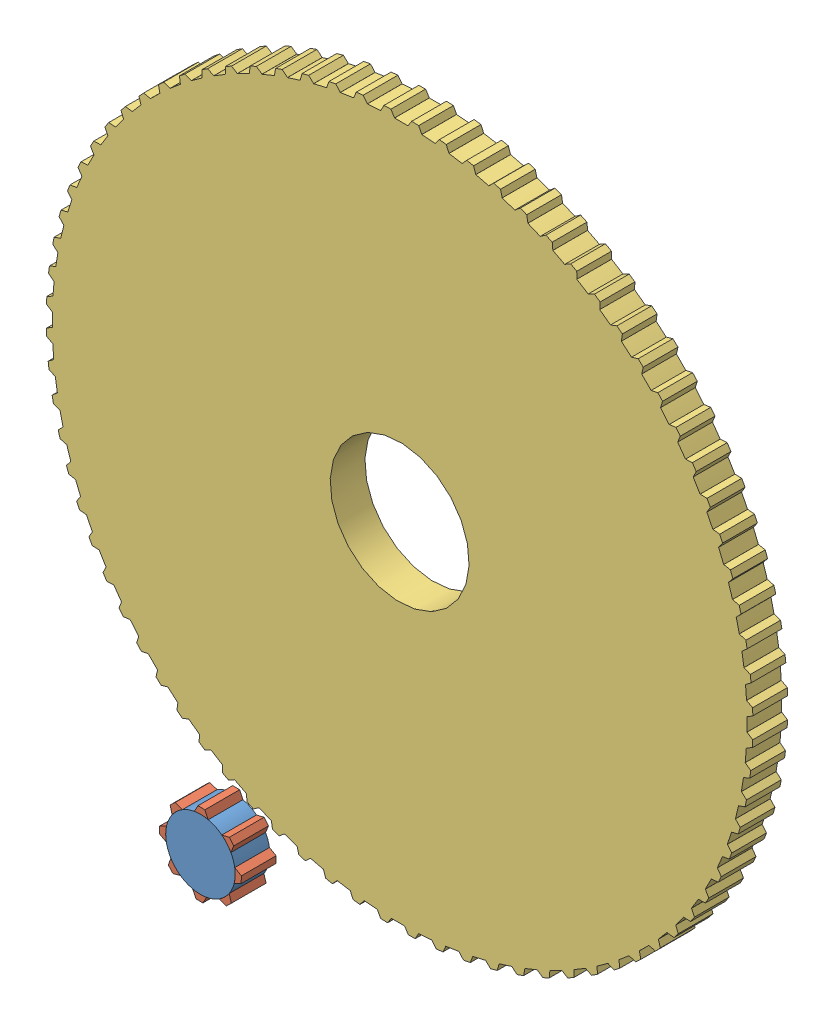
SolidWorks assembly Assem4_2, configuration Default. Lengths in mm.
Overall size (212.15 219.38 20).
10 component instances, 3 part files, 22 mates.
Components (placement in the parent):
- Part2-2: Part2 [Default] at origin size (20 20 10)
- Part3-1: Part3 [Default] x (0.999728 -0.023332 0) z (0 0 1) size (4.02 1.96 10)
- Part3-2: Part3 [Default] x (0.649455 -0.7604 0) z (0 0 1) size (4.02 1.96 10)
- Part3-3: Part3 [Default] x (-0.038663 -0.999252 0) z (0 0 1) size (4.02 1.96 10)
- Part3-4: Part3 [Default] x (-0.718226 -0.69581 0) z (0 0 1) size (4.02 1.96 10)
- Part3-5: Part3 [Default] x (-0.999687 0.025001 0) z (0 0 1) size (4.02 1.96 10)
- Part3-6: Part3 [Default] x (-0.683655 0.729805 0) z (0 0 1) size (4.02 1.96 10)
- Part3-7: Part3 [Default] x (0.015553 0.999879 0) z (0 0 1) size (4.02 1.96 10)
- Part3-8: Part3 [Default] x (0.731594 0.681741 0) z (0 0 1) size (4.02 1.96 10)
- Part1_4-1: Part1_4 [Default] at (47.3332 101.5065 -10) x (0.999033 -0.043972 0) z (0 0 1) size (203.4 203.4 10)
Mates (geometry in assembly coordinates):
- Coincident1: coordinate: point of Part2-2
- Concentric1: concentric aligned: cylinder of Part2-2 through (0 0 10) axis (0 0 -1) radius 10; cylinder of Part3-5 through (0 0 10) axis (0 0 -1) radius 10
- Concentric2: concentric aligned: cylinder of Part2-2 through (0 0 10) axis (0 0 -1) radius 10; cylinder of Part3-8 through (0 0 10) axis (0 0 -1) radius 10
- Concentric3: concentric aligned: cylinder of Part2-2 through (0 0 10) axis (0 0 -1) radius 10; cylinder of Part3-4 through (0 0 10) axis (0 0 -1) radius 10
- Concentric4: concentric aligned: cylinder of Part2-2 through (0 0 10) axis (0 0 -1) radius 10; cylinder of Part3-2 through (0 0 10) axis (0 0 -1) radius 10
- Concentric5: concentric aligned: cylinder of Part2-2 through (0 0 10) axis (0 0 -1) radius 10; cylinder of Part3-3 through (0 0 10) axis (0 0 -1) radius 10
- Concentric6: concentric aligned: cylinder of Part2-2 through (0 0 10) axis (0 0 -1) radius 10; cylinder of Part3-7 through (0 0 10) axis (0 0 -1) radius 10
- Concentric7: concentric aligned: cylinder of Part2-2 through (0 0 10) axis (0 0 -1) radius 10; cylinder of Part3-1 through (0 0 10) axis (0 0 -1) radius 10
- Concentric8: concentric aligned: cylinder of Part2-2 through (0 0 10) axis (0 0 -1) radius 10; cylinder of Part3-6 through (0 0 10) axis (0 0 -1) radius 10
- Coincident3: coincident aligned: plane of Part2-2 through (0 0 10) normal (0 0 1); plane of Part3-8 through (0 0 10) normal (0 0 1)
- Coincident4: coincident aligned: plane of Part2-2 through (0 0 10) normal (0 0 1); plane of Part3-1 through (0 0 10) normal (0 0 1)
- Coincident5: coincident aligned: plane of Part2-2 through (0 0 10) normal (0 0 1); plane of Part3-2 through (0 0 10) normal (0 0 1)
- Coincident6: coincident aligned: plane of Part2-2 through (0 0 10) normal (0 0 1); plane of Part3-3 through (0 0 10) normal (0 0 1)
- Coincident7: coincident aligned: plane of Part2-2 through (0 0 10) normal (0 0 1); plane of Part3-4 through (0 0 10) normal (0 0 1)
- Coincident8: coincident aligned: plane of Part2-2 through (0 0 10) normal (0 0 1); plane of Part3-5 through (0 0 10) normal (0 0 1)
- Coincident9: coincident aligned: plane of Part2-2 through (0 0 10) normal (0 0 1); plane of Part3-7 through (0 0 10) normal (0 0 1)
- Coincident10: coincident aligned: plane of Part2-2 through (0 0 10) normal (0 0 1); plane of Part3-6 through (0 0 10) normal (0 0 1)
- Coincident15: coincident anti-aligned: plane of Part1_4-1 through (47.3332 101.5065 0) normal (0 0 -1)
- Concentric9: concentric aligned: circle of Part1_4-1
- Coincident17: coincident anti-aligned: plane of Part1_4-1 through (47.3332 101.5065 0) normal (0 0 -1)
- Concentric10: concentric: circle of assembly; circle of Part1_4-1; circle of assembly
- Coincident19: coincident: plane of assembly through (0 0 0) normal (0 0 1); plane of Part1_4-1 through (47.3332 101.5065 0) normal (0 0 -1); plane of assembly
